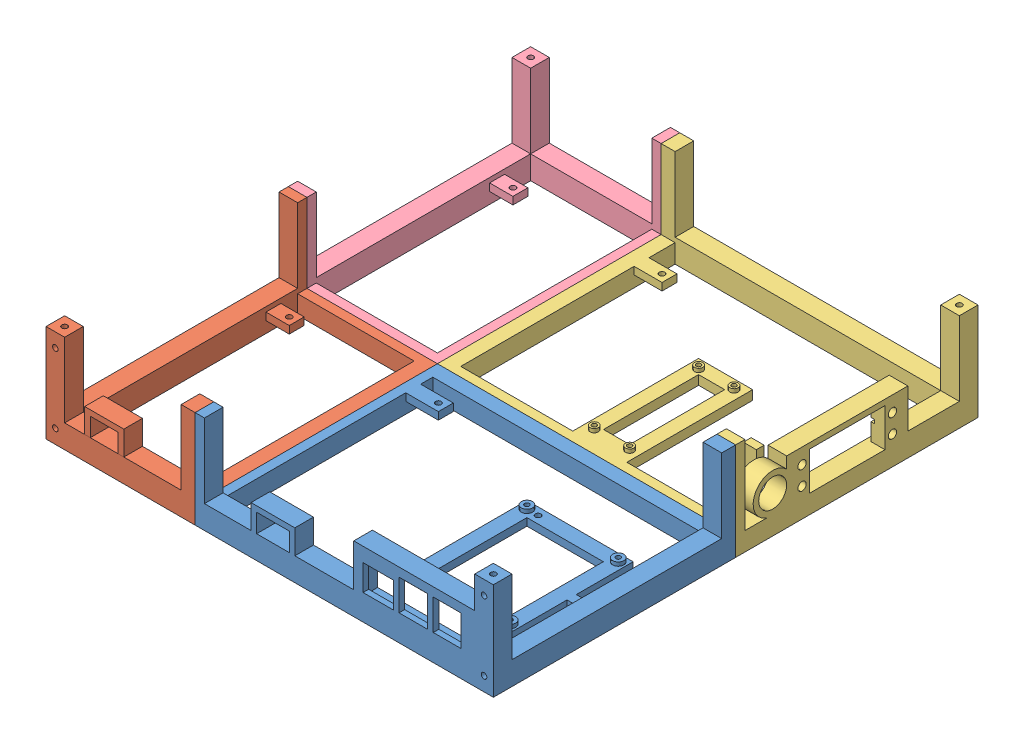
SolidWorks assembly FullBaseTest, configuration Default. Lengths in mm.
Overall size (240 52.3 260).
4 component instances, 4 part files, 9 mates.
Components (placement in the parent):
- BottomLeftTest-1: BottomLeftTest [Default] at origin size (165 52.3 130)
- BottomRightTest-1: BottomRightTest [Default] at (-110 0 0) size (80 52.3 130)
- TopLeftTest-1: TopLeftTest [Default] at (10 0 -125) size (160 52.3 135)
- TopRightTest-1: TopRightTest [Test] at (-110 0 -125) size (85 52.3 130)
Mates (geometry in assembly coordinates):
- Coincident1: coincident anti-aligned: plane of BottomLeftTest-1 through (-75 10 65) normal (-1 0 0); plane of BottomRightTest-1 through (-75 10 65) normal (1 0 0)
- Coincident2: coincident aligned: plane of BottomLeftTest-1 through (-75 10 65) normal (0 0 1); plane of BottomRightTest-1 through (-75 10 65) normal (0 0 1)
- Coincident3: coincident aligned: plane of BottomLeftTest-1 through (0 0 0) normal (0 -1 0); plane of BottomRightTest-1 through (-110 0 0) normal (0 -1 0)
- Coincident6: coincident anti-aligned: plane of BottomLeftTest-1 through (-75 10 -65) normal (0 0 -1); plane of TopLeftTest-1 through (-75 10 -65) normal (0 0 1)
- Coincident7: coincident: plane of BottomLeftTest-1 through (85 10 65) normal (1 0 0); plane of TopLeftTest-1 through (85 10 -65) normal (1 0 0)
- Coincident8: coincident: plane of BottomLeftTest-1 through (0 0 0) normal (0 -1 0); plane of TopLeftTest-1 through (10 0 -125) normal (0 -1 0)
- Coincident9: coincident aligned: plane of BottomRightTest-1 through (-155 10 65) normal (-1 0 0); plane of TopRightTest-1 through (-155 10 -65) normal (-1 0 0)
- Coincident10: coincident aligned: plane of TopLeftTest-1 through (-75 10 -195) normal (0 0 -1); plane of TopRightTest-1 through (-75 10 -195) normal (0 0 -1)
- Coincident11: coincident aligned: plane of BottomRightTest-1 through (-110 0 0) normal (0 -1 0); plane of TopRightTest-1 through (-110 0 -125) normal (0 -1 0)
